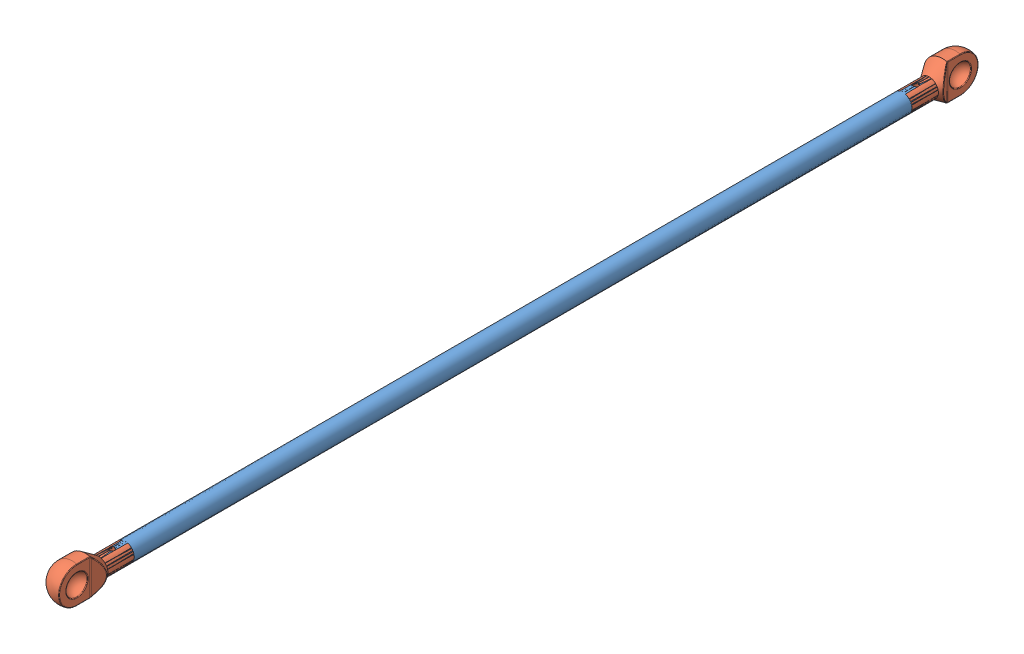
SolidWorks assembly BarreParalleles, configuration Défaut. Lengths in mm.
Overall size (11.85 14 348).
3 component instances, 2 part files, 4 mates.
Components (placement in the parent):
- Pièce4_Tube-1: Pièce4_Tube [Défaut] at (-2.2142 0.2364 157) size (7 7 314)
- Pièce4_Extremetees-1: Pièce4_Extremetees [Défaut] at (-2.2142 0.2364 147) x (0 -1 0) z (0 0 1) size (14 11.85 27)
- Pièce4_Extremetees-2: Pièce4_Extremetees [Défaut] at (-2.2142 0.2364 481) x (0 1 0) z (0 0 -1) size (14 11.85 27)
Mates (geometry in assembly coordinates):
- Coaxiale1: concentric aligned: cylinder of Pièce4_Extremetees-1 through (-2.2142 0.2364 140) axis (0 0 -1) radius 3.5; cylinder of Pièce4_Tube-1 through (-2.2142 0.2364 471) axis (0 0 -1) radius 3
- Coaxiale3: concentric anti-aligned: cylinder of Pièce4_Tube-1 through (-2.2142 10.2364 162) axis (0 -1 0) radius 1; cylinder of Pièce4_Extremetees-1 through (-2.2142 -9.7636 162) axis (0 1 0) radius 1
- Coaxiale4: concentric anti-aligned: cylinder of Pièce4_Tube-1 through (-2.2142 0.2364 471) axis (0 0 -1) radius 3; cylinder of Pièce4_Extremetees-2 through (-2.2142 0.2364 488) axis (0 0 1) radius 3.5
- Coaxiale6: concentric aligned: cylinder of Pièce4_Tube-1 through (-2.2142 10.2364 466) axis (0 -1 0) radius 1; cylinder of Pièce4_Extremetees-2 through (-2.2142 10.2364 466) axis (0 -1 0) radius 1
